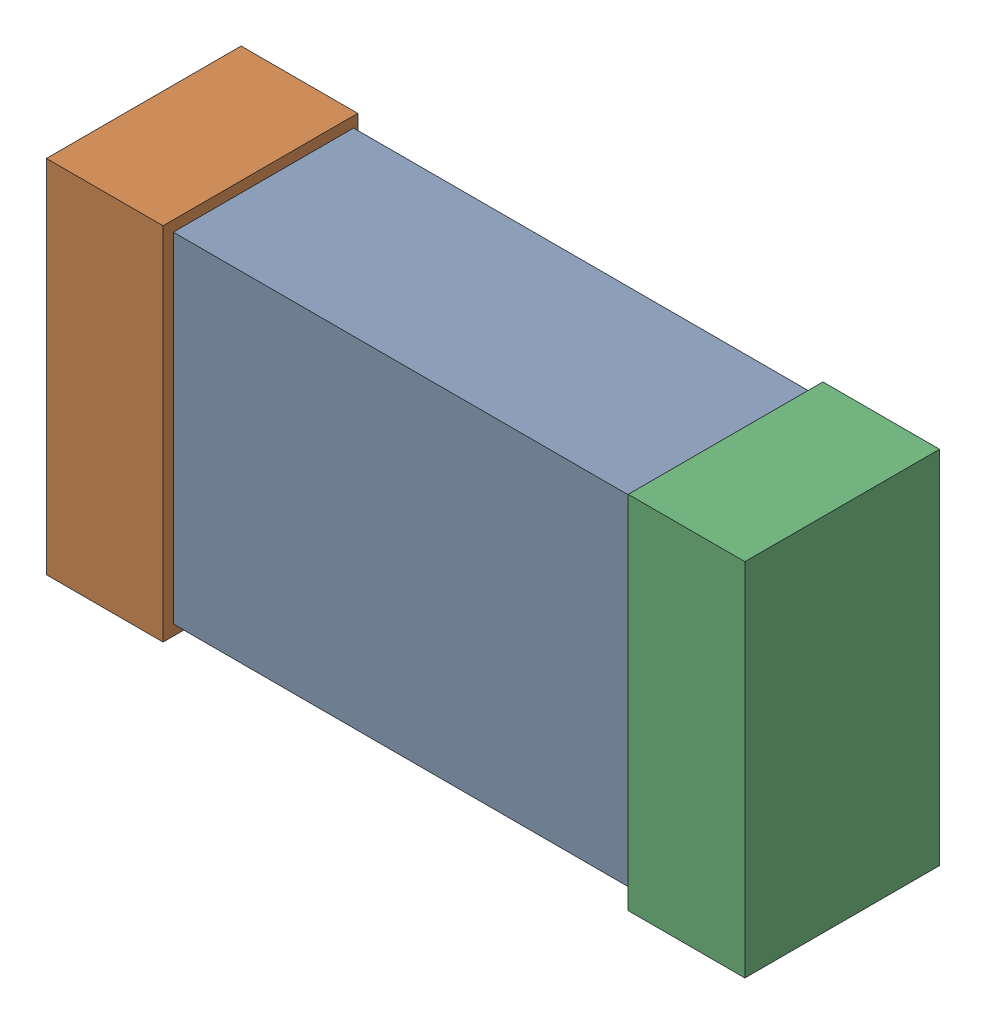
SolidWorks assembly C13, configuration Default. Lengths in mm.
Overall size (1.65 0.85 0.46).
6 component instances, 2 part files, 0 mates.
Components (placement in the parent):
- 432120720_8-1: 432120720_8 [Default] at (44.0653 15.7988 -0.8615) size (1.5 0.8 0.42)
  - Extruded (12)-1: Extruded (12) [Default] at origin size (1.5 0.8 0.42)
- 432120464_16-1: 432120464_16 [Default] at (43.3795 15.7988 -0.8715) size (0.28 0.85 0.46)
  - Extruded (11)-1: Extruded (11) [Default] at origin size (0.28 0.85 0.46)
- 432120464_17-1: 432120464_17 [Default] at (44.751 15.7988 -0.8715) size (0.28 0.85 0.46)
  - Extruded (11)-1: Extruded (11) [Default] at origin size (0.28 0.85 0.46)
